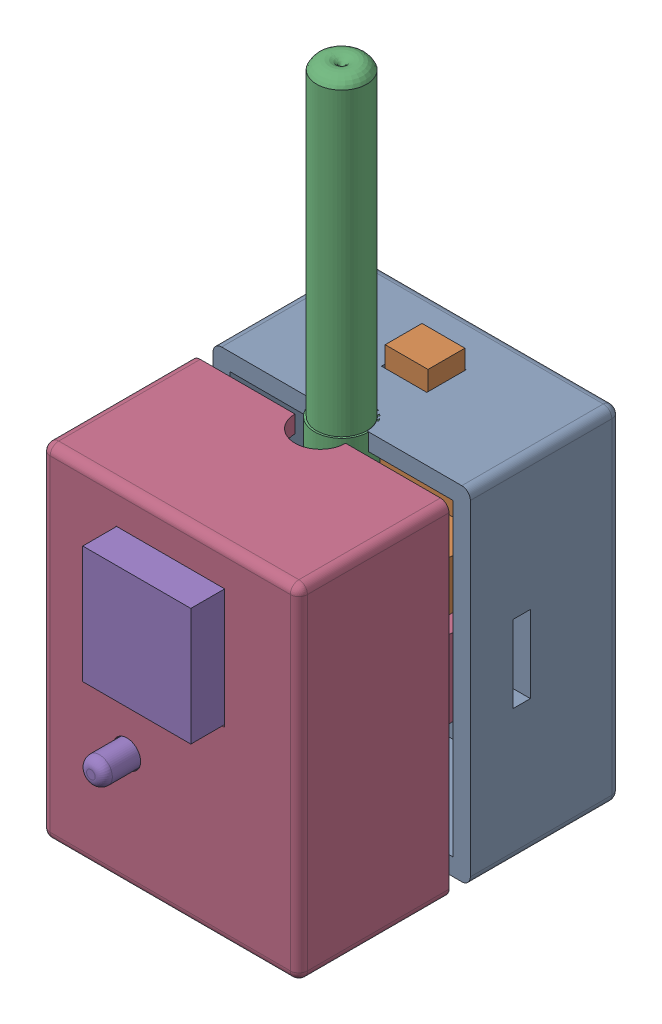
SolidWorks assembly V1, configuration Default. Lengths in mm.
Overall size (30 76.03 41.69).
5 component instances, 5 part files, 8 mates.
Components (placement in the parent):
- V1_Casing_base-1: V1_Casing_base [Default] at (-2.7635 -0.2912 1.6657) size (30 40 17.5)
- LDR-1: LDR [Default] at (-2.7635 2.2088 9.4487) size (14.25 35.2 6.98)
- Thermocouple-1: Thermocouple [Default] at (-2.7635 34.7088 19.1657) x (0 -1 0) z (0 0 1) size (71.07 6.3 6.3)
- V1_Casing_top-1: V1_Casing_top [Default] at (-2.7635 -0.2912 39.1544) x (-1 0 0) z (0 0 -1) size (30 40 24.5)
- Humidity-1: Humidity [Default] at (-2.7635 1.7088 35.6544) size (13.7 32 7.7)
Mates (geometry in assembly coordinates):
- Concentric1: concentric anti-aligned: cylinder of V1_Casing_base-1 through (-2.4635 -6.5162 11.0857) axis (0 0 -1) radius 1.4; cylinder of LDR-1 through (-2.4635 -6.5162 7.2987) axis (0 0 1) radius 1.525
- Concentric2: concentric aligned: cylinder of V1_Casing_base-1 through (-2.7635 -20.2922 19.1657) axis (0 1 0) radius 2.95; cylinder of Thermocouple-1 through (-2.7635 84.7088 19.1657) axis (0 1 0) radius 3.15
- Coincident3: coincident aligned: plane of V1_Casing_base-1 through (-17.7635 19.7088 19.1657) normal (0 1 0); plane of Thermocouple-1 through (-2.7635 19.7088 19.1657) normal (0 1 0)
- Concentric3: concentric aligned: cylinder of V1_Casing_top-1 through (-7.8135 -6.8912 39.1544) axis (0 0 -1) radius 1.6; cylinder of Humidity-1 through (-7.8135 -6.8912 43.3544) axis (0 0 -1) radius 1.5
- Coincident4: coincident anti-aligned: plane of V1_Casing_top-1 through (-2.7635 -0.2912 37.1544) normal (0 0 -1); plane of Humidity-1 through (-2.7635 1.7088 37.1544) normal (0 0 1)
- Coincident5: coincident anti-aligned: plane of V1_Casing_base-1 through (-2.7635 -0.2912 19.1657) normal (0 0 1); plane of V1_Casing_top-1 through (-2.7635 -0.2912 19.1657) normal (0 0 -1)
- Coincident6: coincident aligned: plane of V1_Casing_base-1 through (-17.7635 -20.2912 19.1657) normal (0 -1 0); plane of V1_Casing_top-1 through (12.2365 -20.2912 19.1657) normal (0 -1 0)
- Coincident7: coincident aligned: plane of V1_Casing_base-1 through (-17.7635 19.7088 19.1657) normal (-1 0 0); plane of V1_Casing_top-1 through (-17.7635 19.7088 19.1657) normal (-1 0 0)
